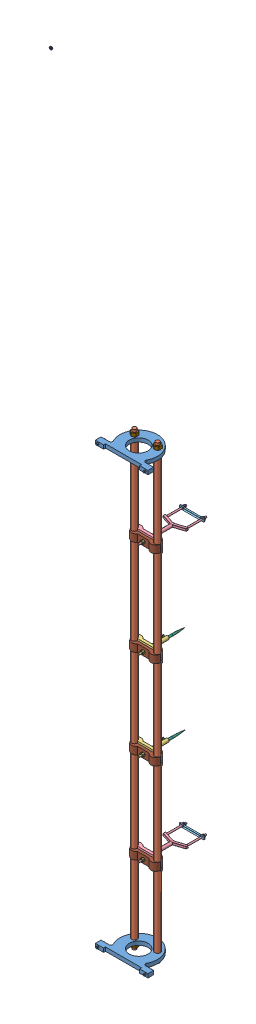
SolidWorks assembly Assem1, configuration Default. Lengths in mm.
Overall size (559.6 2707.45 871.99).
35 component instances, 12 part files, 65 mates.
Components (placement in the parent):
- Part1-1: Part1 [Default] at (-33.5546 66.1187 156.3691) size (140 10 95.39)
- Part2-1: Part2 [Default] at (-64.3364 -1108.8813 136.7965) x (0.853999 0 -0.520275) z (0.520275 0 0.853999) size (15 1200 15)
- Part2-2: Part2 [Default] at (-2.7729 -1108.8813 136.7965) x (0.403255 0 0.915088) z (-0.915088 0 0.403255) size (15 1200 15)
- Part3-2: Part3 [Default] at (-64.3329 -420.1791 136.7965) size (76.56 30 77.11)
- Part4-1: Part4 [Default] at (-64.3329 -166.6611 136.7965) size (76.56 30 153.11)
- Part4-2: Part4 [Default] at (-64.3329 -898.9816 136.7965) size (76.56 30 153.11)
- Part3-3: Part3 [Default] at (-64.3329 -656.5056 136.7965) size (76.56 30 77.11)
- Part1-2: Part1 [Default] at (-33.5546 -1093.8813 156.3691) size (140 10 95.39)
- Part6-1: Part6 [Default] at (-33.5529 -883.9816 14.5192) x (0 1 0) z (0 0 1) size (6.85 65 4)
- Part5-1: Part5 [Default] at (-33.5529 -641.5056 92.6871) x (-0.306259 0.951948 0) z (0 0 1) size (4.98 4.98 85.17)
- Part5-2: Part5 [Default] at (-33.5529 -405.1791 92.6871) x (0.999308 0.037185 0) z (0 0 1) size (4.98 4.98 85.17)
- Part8-1: Part8 [Default] at (-42.0429 -405.1791 83.7541) x (0 -0.314409 0.949288) z (0 -0.949288 -0.314409) size (7.81 7 7.81)
- Part6-2: Part6 [Default] at (-33.5529 -151.6611 14.1999) x (0 1 0) z (0 0 1) size (6.85 65 4)
- Part8-3: Part8 [Default] at (-42.0429 -641.5056 83.7541) x (0 0.961638 -0.274321) z (0 0.274321 0.961638) size (7.81 7 7.81)
- hexagon thin nut (ch)_is-2: hexagon thin nut (ch)_is [IS 1364-4 - M4-N] at (-7.0529 -151.6611 8.7504) x (0.587092 0.80952 0) z (0 0 -1) size (7 8.08 2.2)
- hexagon thin nut (ch)_is-5: hexagon thin nut (ch)_is [IS 1364-4 - M4-N] at (451.2677 1593.4966 873.4768) x (0.923728 0.383049 0) z (0 0 -1) size (7 8.08 2.2)
- hexagon thin nut (ch)_is-7: hexagon thin nut (ch)_is [IS 1364-4 - M4-N] at (-60.0529 -151.6611 7.4342) x (-0.968402 -0.249392 0) z (0 0 -1) size (7 8.08 2.2)
- hexagon thin nut (ch)_is-8: hexagon thin nut (ch)_is [IS 1364-4 - M4-N] at (-7.0529 -883.9816 9.0085) x (-0.822567 -0.568669 0) z (0 0 -1) size (7 8.08 2.2)
- hexagon thin nut (ch)_is-9: hexagon thin nut (ch)_is [IS 1364-4 - M4-N] at (-60.0529 -883.9816 8.3299) x (-0.787872 -0.615839 0) z (0 0 -1) size (7 8.08 2.2)
- hexagon nut style 1_is-1: hexagon nut style 1_is [IS 1364-3 - M10-W-N] at (-2.7729 -1102.2813 136.7965) x (1 0 0) z (0 -1 0) size (16 18.48 8.4)
- hexagon nut style 1_is-2: hexagon nut style 1_is [IS 1364-3 - M10-W-N] at (-64.3364 -1102.2813 136.7965) x (1 0 0) z (0 -1 0) size (16 18.48 8.4)
- hexagon nut style 1_is-3: hexagon nut style 1_is [IS 1364-3 - M10-W-N] at (-64.3364 84.5187 136.7965) x (1 0 0) z (0 1 0) size (16 18.48 8.4)
- hexagon nut style 1_is-4: hexagon nut style 1_is [IS 1364-3 - M10-W-N] at (-2.7729 84.5187 136.7965) x (1 0 0) z (0 1 0) size (16 18.48 8.4)
- Part9-1: Part9 [Default] at (-96.5546 71.1187 184.0269) x (-0.114173 -0.993461 0) z (-0.993461 0.114173 0) size (6.5 21 6.5)
- Part9-2: Part9 [Default] at (29.4454 71.1187 184.4818) x (-0.311023 -0.950402 0) z (-0.950402 0.311023 0) size (6.5 21 6.5)
- Part9-3: Part9 [Default] at (29.4454 -1088.8813 184.3251) x (0.991714 0.128463 0) z (0.128463 -0.991714 0) size (6.5 21 6.5)
- Part9-4: Part9 [Default] at (-96.5546 -1088.8813 184.2042) x (0.865351 -0.501165 0) z (-0.501165 -0.865351 0) size (6.5 21 6.5)
- Part7-1: Part7 [Default] at (-33.5529 -415.1791 136.7965) size (76.56 20 12.5)
- Part7-2: Part7 [Default] at (-33.5529 -651.5056 136.7965) size (76.56 20 12.5)
- Part7-3: Part7 [Default] at (-33.5529 -161.6611 136.7965) size (76.56 20 12.5)
- Part7-4: Part7 [Default] at (-33.5529 -893.9816 136.7965) size (76.56 20 12.5)
- hex nut gradec_bsi-1: hex nut gradec_bsi [BS EN 24034 - M5 - N] at (-33.5529 -151.6611 149.5065) size (8 9.24 5.6)
- hex nut gradec_bsi-2: hex nut gradec_bsi [BS EN 24034 - M5 - N] at (-33.5529 -405.1791 149.5065) size (8 9.24 5.6)
- hex nut gradec_bsi-3: hex nut gradec_bsi [BS EN 24034 - M5 - N] at (-33.5529 -641.5056 149.5065) size (8 9.24 5.6)
- hex nut gradec_bsi-4: hex nut gradec_bsi [BS EN 24034 - M5 - N] at (-33.5529 -883.9816 149.5065) size (8 9.24 5.6)
Mates (geometry in assembly coordinates):
- Concentric1: concentric anti-aligned: cylinder of Part1-1 through (-64.3364 76.1187 136.7965) axis (0 -1 0) radius 5; cylinder of Part2-1 through (-64.3364 66.1187 136.7965) axis (0 1 0) radius 5
- Concentric2: concentric anti-aligned: cylinder of Part1-1 through (-2.7729 76.1187 136.7965) axis (0 -1 0) radius 5; cylinder of Part2-2 through (-2.7729 66.1187 136.7965) axis (0 1 0) radius 5
- Coincident1: coincident anti-aligned: plane of Part1-1 through (-33.5546 66.1187 156.3691) normal (0 -1 0); plane of Part2-1 through (-64.3364 66.1187 136.7965) normal (0 1 0)
- Coincident2: coincident anti-aligned: plane of Part1-1 through (-33.5546 66.1187 156.3691) normal (0 -1 0); plane of Part2-2 through (-2.7729 66.1187 136.7965) normal (0 1 0)
- Concentric4: concentric aligned: cylinder of Part2-2 through (-2.7729 91.1187 136.7965) axis (0 -1 0) radius 7.5; cylinder of Part4-1 through (-2.7729 -136.6611 136.7965) axis (0 -1 0) radius 7.5
- Concentric38: concentric aligned: cylinder of Part2-2 through (-2.7729 91.1187 136.7965) axis (0 -1 0) radius 7.5; cylinder of Part3-2 through (-2.7729 -390.1791 136.7965) axis (0 -1 0) radius 7.5
- Concentric41: concentric aligned: cylinder of Part2-2 through (-2.7729 91.1187 136.7965) axis (0 -1 0) radius 7.5; cylinder of Part3-2 through (-2.7729 -390.1791 136.7965) axis (0 -1 0) radius 7.5
- Parallel15: parallel aligned: line of Part1-1 through (-81.5546 66.1187 196.7567) axis (1 0 0); line of Part3-2 through (-56.8329 -420.1791 136.7965) axis (1 0 0)
- Parallel16: parallel aligned: line of Part1-1 through (-81.5546 66.1187 196.7567) axis (1 0 0); line of Part4-1 through (-56.8329 -166.6611 136.7965) axis (1 0 0)
- Concentric42: concentric aligned: cylinder of Part2-2 through (-2.7729 91.1187 136.7965) axis (0 -1 0) radius 7.5; cylinder of Part3-3 through (-2.7729 -626.5056 136.7965) axis (0 -1 0) radius 7.5
- Parallel17: parallel aligned: line of Part1-1 through (-81.5546 66.1187 196.7567) axis (1 0 0); line of Part3-3 through (-56.8329 -656.5056 136.7965) axis (1 0 0)
- Concentric43: concentric aligned: cylinder of Part2-2 through (-2.7729 91.1187 136.7965) axis (0 -1 0) radius 7.5; cylinder of Part4-2 through (-2.7729 -868.9816 136.7965) axis (0 -1 0) radius 7.5
- Parallel18: parallel aligned: line of Part1-1 through (-81.5546 66.1187 196.7567) axis (1 0 0); line of Part4-2 through (-56.8329 -898.9816 136.7965) axis (1 0 0)
- Concentric44: concentric aligned: cylinder of Part2-2 through (-2.7729 -1083.8813 136.7965) axis (0 -1 0) radius 5; cylinder of Part1-2 through (-2.7729 -1083.8813 136.7965) axis (0 -1 0) radius 5
- Concentric45: concentric aligned: cylinder of Part2-1 through (-64.3364 -1083.8813 136.7965) axis (0 -1 0) radius 5; cylinder of Part1-2 through (-64.3364 -1083.8813 136.7965) axis (0 -1 0) radius 5
- Coincident9: coincident anti-aligned: plane of Part2-2 through (-2.7729 -1083.8813 136.7965) normal (0 -1 0); plane of Part1-2 through (-33.5546 -1083.8813 156.3691) normal (0 1 0)
- Concentric46: concentric anti-aligned: cylinder of Part3-3 through (-33.5529 -641.5056 79.6871) axis (0 0 1) radius 2.5; cylinder of Part5-1 through (-33.5529 -641.5056 32.5128) axis (0 0 -1) radius 2.49
- Parallel19: parallel anti-aligned: plane of Part3-3 through (-49.0515 -626.5056 129.6871) normal (0 0 -1); plane of Part5-1 through (-33.5529 -641.5056 117.6871) normal (0 0 1)
- Distance3: distance = 12 mm anti-aligned: plane of Part3-3 through (-49.0515 -626.5056 129.6871) normal (0 0 -1); plane of Part5-1 through (-33.5529 -641.5056 117.6871) normal (0 0 1)
- Concentric47: concentric anti-aligned: cylinder of Part3-2 through (-33.5529 -405.1791 79.6871) axis (0 0 1) radius 2.5; cylinder of Part5-2 through (-33.5529 -405.1791 32.5128) axis (0 0 -1) radius 2.49
- Distance4: distance = 12 mm anti-aligned: plane of Part5-2 through (-33.5529 -405.1791 117.6871) normal (0 0 1); plane of Part3-2 through (-49.0515 -390.1791 129.6871) normal (0 0 -1)
- Concentric49: concentric aligned: cylinder of Part3-2 through (4.7281 -405.1791 83.7541) axis (-1 0 0) radius 1.5; cylinder of Part8-1 through (-36.0429 -405.1791 83.7541) axis (-1 0 0) radius 1.5
- Tangent7: tangent anti-aligned: cylinder of Part5-2 through (-33.5529 -405.1791 32.5128) axis (0 0 -1) radius 2.49; plane of Part8-1 through (-36.0429 -405.1791 83.7541) normal (1 0 0)
- Concentric50: concentric aligned: cylinder of Part4-2 through (-7.0529 -883.9816 64.9084) axis (0 0 -1) radius 2; cylinder of Part6-1 through (-7.0529 -883.9816 22.7192) axis (0 0 -1) radius 2.01
- Concentric51: concentric aligned: cylinder of Part4-2 through (-60.0529 -883.9816 64.9137) axis (0 0 -1) radius 2; cylinder of Part6-1 through (-60.0529 -883.9816 22.7192) axis (0 0 -1) radius 2.01
- Concentric52: concentric aligned: cylinder of Part4-1 through (-7.0529 -151.6611 64.9084) axis (0 0 -1) radius 2; cylinder of Part6-2 through (-7.0529 -151.6611 22.3999) axis (0 0 -1) radius 2.01
- Concentric53: concentric aligned: cylinder of Part4-1 through (-60.0529 -151.6611 64.9137) axis (0 0 -1) radius 2; cylinder of Part6-2 through (-60.0529 -151.6611 22.3999) axis (0 0 -1) radius 2.01
- Concentric54: concentric aligned: cylinder of Part3-3 through (4.7281 -641.5056 83.7541) axis (-1 0 0) radius 1.5; cylinder of Part8-3 through (-36.0429 -641.5056 83.7541) axis (-1 0 0) radius 1.5
- Tangent9: tangent anti-aligned: cylinder of Part5-1 through (-33.5529 -641.5056 32.5128) axis (0 0 -1) radius 2.49; plane of Part8-3 through (-36.0429 -641.5056 83.7541) normal (1 0 0)
- Concentric57: concentric aligned: cylinder of Part4-1 through (-7.0529 -151.6611 64.9084) axis (0 0 -1) radius 2; cylinder of hexagon thin nut (ch)_is-2 through (-7.0529 -151.6611 33.7879) axis (0 0 -1) radius 2
- Concentric62: concentric aligned: cylinder of Part4-1 through (-60.0529 -151.6611 64.9137) axis (0 0 -1) radius 2; cylinder of hexagon thin nut (ch)_is-7 through (-60.0529 -151.6611 32.4717) axis (0 0 -1) radius 2
- Concentric63: concentric aligned: cylinder of Part4-2 through (-7.0529 -883.9816 64.9084) axis (0 0 -1) radius 2; cylinder of hexagon thin nut (ch)_is-8 through (-7.0529 -883.9816 34.046) axis (0 0 -1) radius 2
- Concentric64: concentric aligned: cylinder of Part4-2 through (-60.0529 -883.9816 64.9137) axis (0 0 -1) radius 2; cylinder of hexagon thin nut (ch)_is-9 through (-60.0529 -883.9816 33.3674) axis (0 0 -1) radius 2
- Concentric66: concentric aligned: cylinder of Part1-2 through (-2.7729 -1083.8813 136.7965) axis (0 -1 0) radius 5; cylinder of hexagon nut style 1_is-1 through (-2.7729 -1077.2438 136.7965) axis (0 -1 0) radius 5
- Coincident18: coincident anti-aligned: plane of Part1-2 through (-33.5546 -1093.8813 156.3691) normal (0 -1 0); plane of hexagon nut style 1_is-1 through (-18.7729 -1093.8813 136.7965) normal (0 1 0)
- Concentric67: concentric aligned: cylinder of Part1-2 through (-64.3364 -1083.8813 136.7965) axis (0 -1 0) radius 5; cylinder of hexagon nut style 1_is-2 through (-64.3364 -1077.2438 136.7965) axis (0 -1 0) radius 5
- Coincident19: coincident anti-aligned: plane of Part1-2 through (-33.5546 -1093.8813 156.3691) normal (0 -1 0); plane of hexagon nut style 1_is-2 through (-80.3364 -1093.8813 136.7965) normal (0 1 0)
- Concentric68: concentric anti-aligned: cylinder of Part1-1 through (-64.3364 76.1187 136.7965) axis (0 -1 0) radius 5; cylinder of hexagon nut style 1_is-3 through (-64.3364 59.4812 136.7965) axis (0 1 0) radius 5
- Coincident20: coincident anti-aligned: plane of Part1-1 through (-33.5546 76.1187 156.3691) normal (0 1 0); plane of hexagon nut style 1_is-3 through (-80.3364 76.1187 136.7965) normal (0 -1 0)
- Concentric69: concentric anti-aligned: cylinder of Part1-1 through (-2.7729 76.1187 136.7965) axis (0 -1 0) radius 5; cylinder of hexagon nut style 1_is-4 through (-2.7729 59.4812 136.7965) axis (0 1 0) radius 5
- Coincident21: coincident anti-aligned: plane of Part1-1 through (-33.5546 76.1187 156.3691) normal (0 1 0); plane of hexagon nut style 1_is-4 through (-18.7729 76.1187 136.7965) normal (0 -1 0)
- Concentric70: concentric aligned: cylinder of Part1-1 through (-96.5546 71.1187 201.7567) axis (0 0 -1) radius 2.5; cylinder of Part9-1 through (-96.5546 71.1187 205.0269) axis (0 0 -1) radius 2.5
- Concentric72: concentric aligned: cylinder of Part1-1 through (29.4454 71.1187 201.7567) axis (0 0 -1) radius 2.5; cylinder of Part9-2 through (29.4454 71.1187 205.4818) axis (0 0 -1) radius 2.5
- Concentric73: concentric aligned: cylinder of Part1-2 through (-96.5546 -1088.8813 201.7567) axis (0 0 -1) radius 2.5; cylinder of Part9-4 through (-96.5546 -1088.8813 205.2042) axis (0 0 -1) radius 2.5
- Concentric74: concentric aligned: cylinder of Part1-2 through (29.4454 -1088.8813 201.7567) axis (0 0 -1) radius 2.5; cylinder of Part9-3 through (29.4454 -1088.8813 205.3251) axis (0 0 -1) radius 2.5
- Concentric75: concentric aligned: cylinder of Part3-2 through (-33.5529 -405.1791 156.7965) axis (0 0 -1) radius 2; circle of Part7-1
- Coincident22: coincident anti-aligned: plane of Part3-2 through (-56.8329 -390.1791 136.7965) normal (0 0 1); plane of Part7-1 through (-56.8329 -395.1791 136.7965) normal (0 0 -1)
- Concentric77: concentric aligned: cylinder of Part3-3 through (-33.5529 -641.5056 156.7965) axis (0 0 -1) radius 2; cylinder of Part7-2 through (-33.5529 -641.5056 156.7965) axis (0 0 -1) radius 2.01
- Coincident23: coincident anti-aligned: plane of Part3-3 through (-56.8329 -626.5056 136.7965) normal (0 0 1); plane of Part7-2 through (-56.8329 -631.5056 136.7965) normal (0 0 -1)
- Parallel21: parallel anti-aligned: line of Part3-3 through (-56.8329 -626.5056 136.7965) axis (1 0 0); line of Part7-2 through (-10.2729 -631.5056 136.7965) axis (-1 0 0)
- Parallel22: parallel anti-aligned: line of Part3-2 through (-56.8329 -420.1791 136.7965) axis (1 0 0); line of Part7-1 through (-10.2729 -415.1791 136.7965) axis (-1 0 0)
- Concentric78: concentric aligned: cylinder of Part4-1 through (-33.5529 -151.6611 156.7965) axis (0 0 -1) radius 2; cylinder of Part7-3 through (-33.5529 -151.6611 156.7965) axis (0 0 -1) radius 2.01
- Coincident26: coincident anti-aligned: plane of Part4-1 through (-56.8329 -136.6611 136.7965) normal (0 0 1); plane of Part7-3 through (-56.8329 -141.6611 136.7965) normal (0 0 -1)
- Parallel23: parallel anti-aligned: line of Part4-1 through (-56.8329 -166.6611 136.7965) axis (1 0 0); line of Part7-3 through (-10.2729 -161.6611 136.7965) axis (-1 0 0)
- Concentric79: concentric aligned: cylinder of Part7-4 through (-33.5529 -883.9816 156.7965) axis (0 0 -1) radius 2.01; cylinder of Part4-2 through (-33.5529 -883.9816 156.7965) axis (0 0 -1) radius 2
- Coincident28: coincident anti-aligned: plane of Part4-2 through (-56.8329 -868.9816 136.7965) normal (0 0 1); plane of Part7-4 through (-56.8329 -873.9816 136.7965) normal (0 0 -1)
- Parallel24: parallel anti-aligned: line of Part4-2 through (-56.8329 -898.9816 136.7965) axis (1 0 0); line of Part7-4 through (-10.2729 -893.9816 136.7965) axis (-1 0 0)
- Concentric80: concentric anti-aligned: cylinder of Part7-3 through (-33.5529 -151.6611 156.7965) axis (0 0 -1) radius 2.01; cylinder of hex nut gradec_bsi-1 through (-33.5529 -151.6611 124.469) axis (0 0 1) radius 2.5
- Coincident30: coincident anti-aligned: plane of Part7-3 through (-49.0519 -141.6611 143.9065) normal (0 0 1); plane of hex nut gradec_bsi-1 through (-33.5529 -147.0423 143.9065) normal (0 0 -1)
- Concentric81: concentric anti-aligned: cylinder of Part7-1 through (-33.5529 -405.1791 156.7965) axis (0 0 -1) radius 2.01; cylinder of hex nut gradec_bsi-2 through (-33.5529 -405.1791 124.469) axis (0 0 1) radius 2.5
- Coincident31: coincident anti-aligned: plane of Part7-1 through (-49.0519 -395.1791 143.9065) normal (0 0 1); plane of hex nut gradec_bsi-2 through (-33.5529 -400.5603 143.9065) normal (0 0 -1)
- Concentric82: concentric anti-aligned: cylinder of Part7-2 through (-33.5529 -641.5056 156.7965) axis (0 0 -1) radius 2.01; cylinder of hex nut gradec_bsi-3 through (-33.5529 -641.5056 124.469) axis (0 0 1) radius 2.5
- Coincident32: coincident anti-aligned: plane of Part7-2 through (-49.0519 -631.5056 143.9065) normal (0 0 1); plane of hex nut gradec_bsi-3 through (-33.5529 -636.8868 143.9065) normal (0 0 -1)
- Concentric83: concentric anti-aligned: cylinder of Part7-4 through (-33.5529 -883.9816 156.7965) axis (0 0 -1) radius 2.01; cylinder of hex nut gradec_bsi-4 through (-33.5529 -883.9816 124.469) axis (0 0 1) radius 2.5
- Coincident33: coincident anti-aligned: plane of Part7-4 through (-49.0519 -873.9816 143.9065) normal (0 0 1); plane of hex nut gradec_bsi-4 through (-33.5529 -879.3628 143.9065) normal (0 0 -1)
